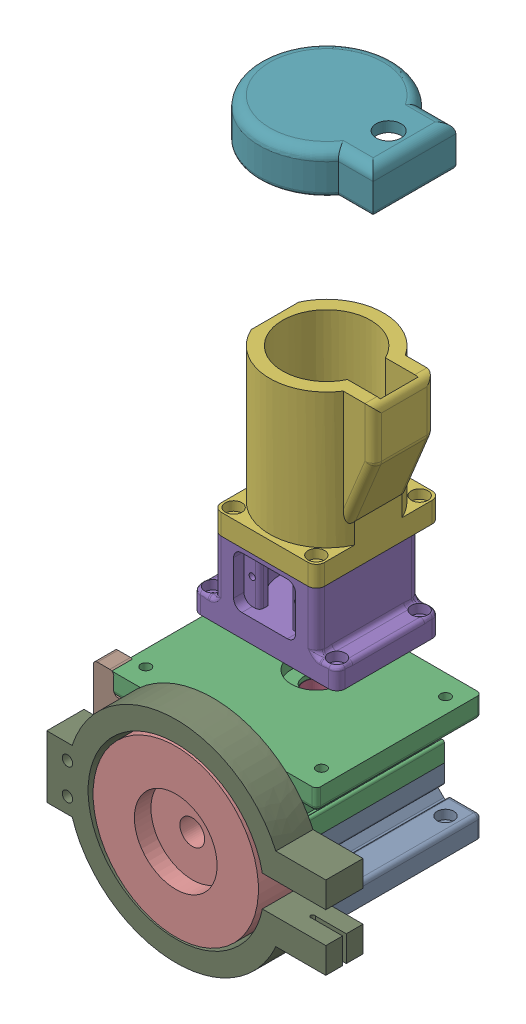
SolidWorks assembly g 3.0, configuration Défaut. Lengths in mm.
Overall size (135 331.17 105.5).
10 component instances, 9 part files, 25 mates.
Components (placement in the parent):
- bot inf v2-1: bot inf v2 [Défaut] at origin size (100 22 86.15)
- engrenage-1: engrenage [Défaut] at (-50 22 -32.2) x (0 0 1) z (0.285018 -0.958522 0) size (21.33 31.78 31.78)
- bot sup v2-1: bot sup v2 [Défaut] at (-100 50 0) size (100 38 86.15)
- engrenage-2: engrenage [Défaut] at (-50 39 -50) x (0 1 0) z (0.996633 0 0.081992) size (21.33 31.78 31.78)
- top avec fenetre-1: top avec fenetre [Défaut] at (-85 80 -25) size (70 38 50)
- top moteur-1: top moteur [Défaut] at (-75 118 -25) size (62.5 75.3 60)
- top moteur couvercle-1: top moteur couvercle [Défaut] at (-50 278.3 -55) size (75 20 65)
- clip gearbox  coté machoire-1: clip gearbox  coté machoire [Défaut] at (-84.9 22.2414 -10) size (32.85 54.88 10)
- machoire-1: machoire [Défaut] at (-49.9 22.2414 0) x (-1 0 0) z (0 0 1) size (135 104.62 18)
- tambour-1: tambour [Défaut] at (-50 22 18) x (0.514143 0.857705 0) z (0 0 1) size (80 80 18)
Mates (geometry in assembly coordinates):
- Coïncidente1: coincident anti-aligned: plane of bot inf v2-1 through (0 0 0) normal (0 -1 0)
- Coïncidente2: coincident aligned: plane of bot inf v2-1 through (0 10 0) normal (1 0 0)
- Coïncidente3: coincident aligned: plane of bot inf v2-1 through (0 10 0) normal (0 0 1)
- Coïncidente6: coincident aligned: plane of bot inf v2-1 through (0 10 0) normal (0 0 1); plane of bot sup v2-1 through (-100 60 0) normal (0 0 1)
- Coïncidente7: coincident aligned: plane of bot inf v2-1 through (0 10 0) normal (1 0 0); plane of bot sup v2-1 through (0 60 0) normal (1 0 0)
- Coïncidente8: coincident anti-aligned: plane of bot sup v2-1 through (-100 52 0) normal (0 -1 0); plane of engrenage-2 through (-50 52 -50) normal (0 1 0)
- Coaxiale2: concentric aligned: cylinder of bot sup v2-1 through (-50 22 -50) axis (0 1 0) radius 6.2; cylinder of engrenage-2 through (-50 52 -50) axis (0 1 0) radius 6
- Coïncidente9: coincident anti-aligned: plane of bot inf v2-1 through (0 22 0) normal (0 1 0); plane of bot sup v2-1 through (-100 22 0) normal (0 -1 0)
- Distance2: distance = 20 mm anti-aligned: plane of bot sup v2-1 through (-100 60 0) normal (0 1 0); plane of top avec fenetre-1 through (-85 80 -25) normal (0 -1 0)
- Coaxiale3: concentric aligned: cylinder of bot sup v2-1 through (-50 54 -50) axis (0 1 0) radius 12.1; cylinder of top avec fenetre-1 through (-50 91 -50) axis (0 1 0) radius 17.5
- Coïncidente12: coincident anti-aligned: plane of top avec fenetre-1 through (-85 118 -25) normal (0 1 0); plane of top moteur-1 through (-75 118 -25) normal (0 -1 0)
- Coïncidente13: coincident aligned: plane of top avec fenetre-1 through (-85 90 -25) normal (0 0 1); plane of top moteur-1 through (-75 128 -25) normal (0 0 1)
- Coïncidente14: coincident aligned: plane of top avec fenetre-1 through (-75 110 -25) normal (-1 0 0); plane of top moteur-1 through (-75 128 -25) normal (-1 0 0)
- Coaxiale4: concentric aligned: cylinder of top moteur-1 through (-50 193.3 -55) axis (0 -1 0) radius 27.5; cylinder of top moteur couvercle-1 through (-50 293.3 -55) axis (0 -1 0) radius 27.5
- DistanceLimite1: limit distance = 100 mm anti-aligned: plane of top moteur couvercle-1 through (-50 293.3 -55) normal (0 -1 0); plane of top moteur-1 through (-75 193.3 -25) normal (0 1 0)
- Coaxiale5: concentric anti-aligned: cylinder of engrenage-1 through (-50 22 -19.2) axis (0 0 1) radius 6; cylinder of bot sup v2-1 through (-50 22 -86.15) axis (0 0 -1) radius 8
- Distance3: distance = 5 mm anti-aligned: plane of bot inf v2-1 through (0 22 -14.2) normal (0 0 -1); plane of engrenage-1 through (-50 22 -19.2) normal (0 0 1)
- Coïncidente15: coincident anti-aligned: plane of bot inf v2-1 through (-82 0 -86.15) normal (-1 0 0); plane of clip gearbox  coté machoire-1 through (-82 22.2414 0) normal (1 0 0)
- Coïncidente16: coincident anti-aligned: plane of bot inf v2-1 through (-46.6213 46.6213 -86.15) normal (0.707107 -0.707107 0); plane of clip gearbox  coté machoire-1 through (-77.9506 15.292 0) normal (-0.707107 0.707107 0)
- Coïncidente17: coincident aligned: plane of bot inf v2-1 through (0 10 0) normal (0 0 1); plane of clip gearbox  coté machoire-1 through (-84.9 22.2414 0) normal (0 0 1)
- Coaxiale6: concentric aligned: cylinder of clip gearbox  coté machoire-1 through (-102.4 29.7414 0) axis (0 0 -1) radius 2.5; cylinder of machoire-1 through (-102.4 29.7414 18) axis (0 0 -1) radius 2.5
- Coaxiale7: concentric aligned: cylinder of clip gearbox  coté machoire-1 through (-102.4 14.7414 0) axis (0 0 -1) radius 2.5; cylinder of machoire-1 through (-102.4 14.7414 18) axis (0 0 -1) radius 2.5
- Coïncidente18: coincident anti-aligned: plane of clip gearbox  coté machoire-1 through (-84.9 22.2414 0) normal (0 0 1); plane of machoire-1 through (-49.9 22.2414 0) normal (0 0 -1)
- Coaxiale8: concentric anti-aligned: circle of bot sup v2-1; circle of tambour-1
- Coïncidente19: coincident anti-aligned: plane of bot sup v2-1 through (-100 60 0) normal (0 0 1); plane of tambour-1 through (-50 22 0) normal (0 0 -1)
